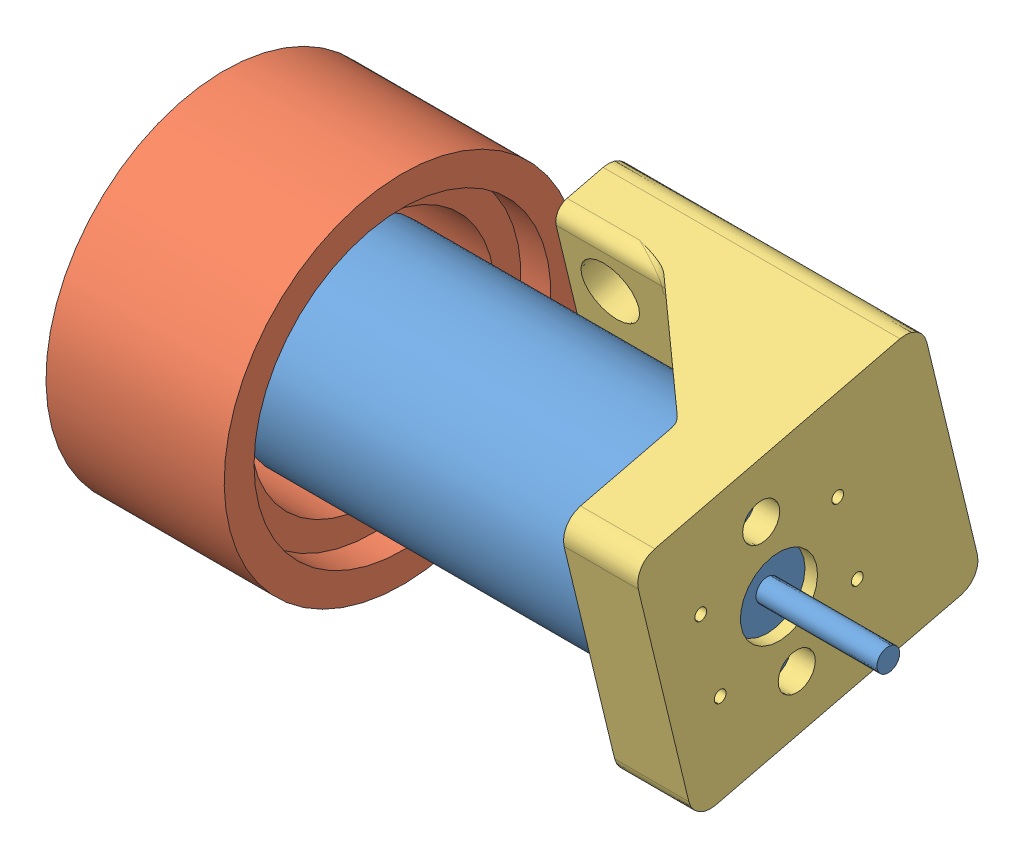
SolidWorks assembly Assem1, configuration Default. Lengths in mm.
Overall size (113.8 86 86).
3 component instances, 3 part files, 3 mates.
Components (placement in the parent):
- motor_withshaft-1: motor_withshaft [Default] at (114.1916 63.2299 66.0433) size (113.8 34.9 34.9)
- reactionWheel_noshaft-1: reactionWheel_noshaft [Default] at (21.0703 73.5429 66.0433) x (0 -0.760425 0.649425) z (0 0.649425 0.760425) size (61 30.5 61)
- reactionWheelMount-1: reactionWheelMount [Default] at (52.024 80.7007 36.4157) x (0 -0.972036 -0.234834) z (0 -0.234834 0.972036) size (44.45 50.8 50.8)
Mates (geometry in assembly coordinates):
- Concentric4: concentric anti-aligned: cylinder of motor_withshaft-1 through (7.733 73.5429 66.0433) axis (-1 0 0) radius 2.95; cylinder of reactionWheel_noshaft-1 through (76.7648 73.5429 66.0433) axis (1 0 0) radius 2.95
- Coincident2: coincident: plane of motor_withshaft-1 through (98.633 90.9929 66.0433) normal (1 0 0); plane of reactionWheelMount-1 through (98.633 78.3967 71.5008) normal (-1 0 0)
- Concentric5: concentric aligned: cylinder of motor_withshaft-1 through (7.733 73.5429 66.0433) axis (-1 0 0) radius 17.45; cylinder of reactionWheelMount-1 through (152.7542 73.5429 66.0433) axis (-1 0 0) radius 17.653
